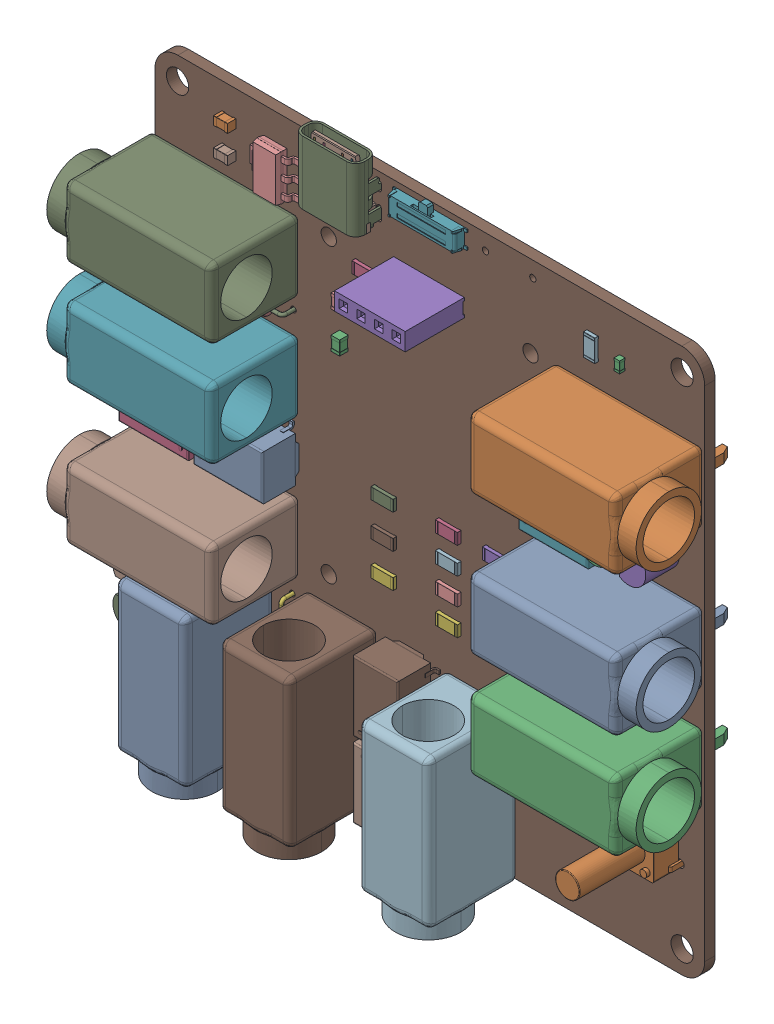
SolidWorks assembly PCB, configuration Default. Lengths in mm.
Overall size (84.69 83.26 18.9).
47 component instances, 13 part files, 0 mates.
Components (placement in the parent):
- Logic testing(2)-1: Logic testing(2) [Default] at origin size (84.69 83.26 18.9)
  - Relay_DPDT_Omron_G6K-2F-1: Relay_DPDT_Omron_G6K-2F [Default] at (-23.44 -1.875 1.595) x (0 1 0) z (0 0 1) size (7.8 10 5.58)
  - SW_PUSH_6mm_H13mm-1: SW_PUSH_6mm_H13mm [Default] at (36 -25.375 1.595) x (-1 0 0) z (0 0 1) size (7.17 6 16.5)
  - C_0603_1608Metric-1: C_0603_1608Metric [Default] at (27.75 32.875 1.595) x (0 1 0) z (0 0 1) size (1.6 0.8 0.8)
  - R_1206_3216Metric-1: R_1206_3216Metric [Default] at (-9 25.875 1.595) size (3.2 1.6 0.55)
  - PinSocket_1x04_P2.54mm_Vertical-1: PinSocket_1x04_P2.54mm_Vertical [Default] at (3.775 28.375 1.595) x (0 -1 0) z (0 0 1) size (2.54 10.16 11.6)
  - R_1206_3216Metric-2: R_1206_3216Metric [Default] at (9.75 -4.2083 1.595) size (3.2 1.6 0.55)
  - 4mm PCB Mount-1: 4mm PCB Mount [Default] at (-29.04 8.125 8.095) x (0 1 0) z (1 0 0) size (10.21 18.8 24)
  - 4mm PCB Mount-2: 4mm PCB Mount [Default] at (-29.04 -11.875 8.095) x (0 1 0) z (1 0 0) size (10.21 18.8 24)
  - 4mm PCB Mount-3: 4mm PCB Mount [Default] at (-29.04 23.125 8.095) x (0 1 0) z (1 0 0) size (10.21 18.8 24)
  - SOT-223-1: SOT-223 [Default] at (-22 32.375 1.595) x (-1 0 0) z (0 0 1) size (7 6.5 1.7)
  - R_1206_3216Metric-3: R_1206_3216Metric [Default] at (-6.25 -5.75 1.595) x (-1 0 0) z (0 0 1) size (3.2 1.6 0.55)
  - R_1206_3216Metric-4: R_1206_3216Metric [Default] at (23.5 32.875 1.595) x (0 1 0) z (0 0 1) size (3.2 1.6 0.55)
  - 4mm PCB Mount-4: 4mm PCB Mount [Default] at (29 3.375 8.095) x (0 -1 0) z (-1 0 0) size (10.21 18.8 24)
  - 4mm PCB Mount-5: 4mm PCB Mount [Default] at (29 23.375 8.095) x (0 -1 0) z (-1 0 0) size (10.21 18.8 24)
  - 4mm PCB Mount-6: 4mm PCB Mount [Default] at (29 -11.625 8.095) x (0 -1 0) z (-1 0 0) size (10.21 18.8 24)
  - R_1206_3216Metric-5: R_1206_3216Metric [Default] at (9.75 -8.0417 1.595) size (3.2 1.6 0.55)
  - TO-92_Inline-1: TO-92_Inline [Default] at (36 16.625 1.595) x (0 -1 0) z (0 0 1) size (4.83 3.75 9.8)
  - R_1206_3216Metric-6: R_1206_3216Metric [Default] at (3 -11.875 1.595) size (3.2 1.6 0.55)
  - SW_SP3T_PCM13-1: SW_SP3T_PCM13 [Default] at (0.25 36.745 1.595) x (-1 0 0) z (0 0 1) size (10.65 4.65 2)
  - TO-92_Inline-2: TO-92_Inline [Default] at (-37.02 -21.485 1.595) size (4.83 3.75 9.8)
  - USB_C_Receptacle_GCT_USB4085-1: USB_C_Receptacle_GCT_USB4085 [Default] at (-8.625 32.95 1.595) x (-1 0 0) z (0 0 1) size (8.94 9.17 5.56)
  - Relay_DPDT_Omron_G6K-2F-2: Relay_DPDT_Omron_G6K-2F [Default] at (23.25 13.375 1.595) x (0 1 0) z (0 0 1) size (7.8 10 5.58)
  - Relay_DPDT_Omron_G6K-2F-3: Relay_DPDT_Omron_G6K-2F [Default] at (-2.25 -33.275 1.595) size (7.8 10 5.58)
  - D_DO-35_SOD27_P7.62mm_Horizontal-1: D_DO-35_SOD27_P7.62mm_Horizontal [Default] at (-27.21 15.775 1.595) size (8.12 2.02 5.01)
  - Relay_DPDT_Omron_G6K-2F-4: Relay_DPDT_Omron_G6K-2F [Default] at (-2.25 -22.465 1.595) x (-1 0 0) z (0 0 1) size (7.8 10 5.58)
  - R_1206_3216Metric-7: R_1206_3216Metric [Default] at (3 -4.2083 1.595) x (-1 0 0) z (0 0 1) size (3.2 1.6 0.55)
  - D_DO-35_SOD27_P7.62mm_Horizontal-2: D_DO-35_SOD27_P7.62mm_Horizontal [Default] at (-19.75 -29.775 1.595) x (0 -1 0) z (0 0 1) size (8.12 2.02 5.01)
  - TO-92_Inline-3: TO-92_Inline [Default] at (31 16.645 1.595) x (0 -1 0) z (0 0 1) size (4.83 3.75 9.8)
  - Relay_DPDT_Omron_G6K-2F-5: Relay_DPDT_Omron_G6K-2F [Default] at (-34.19 -1.875 1.595) x (0 -1 0) z (0 0 1) size (7.8 10 5.58)
  - R_1206_3216Metric-8: R_1206_3216Metric [Default] at (9.75 -0.375 1.595) size (3.2 1.6 0.55)
  - R_1206_3216Metric-9: R_1206_3216Metric [Default] at (-6.25 -10.625 1.595) x (-1 0 0) z (0 0 1) size (3.2 1.6 0.55)
  - D_DO-35_SOD27_P7.62mm_Horizontal-3: D_DO-35_SOD27_P7.62mm_Horizontal [Default] at (-29.46 15.775 1.595) x (-1 0 0) z (0 0 1) size (8.12 2.02 5.01)
  - R_1206_3216Metric-10: R_1206_3216Metric [Default] at (-6.25 -0.875 1.595) x (-1 0 0) z (0 0 1) size (3.2 1.6 0.55)
  - R_1206_3216Metric-11: R_1206_3216Metric [Default] at (3 -8.0417 1.595) size (3.2 1.6 0.55)
  - 4mm PCB Mount-7: 4mm PCB Mount [Default] at (-12.25 -28.375 8.095) x (-1 0 0) z (0 1 0) size (10.21 18.8 24)
  - 4mm PCB Mount-8: 4mm PCB Mount [Default] at (7.75 -28.375 8.095) x (-1 0 0) z (0 1 0) size (10.21 18.8 24)
  - 4mm PCB Mount-9: 4mm PCB Mount [Default] at (-27.25 -28.375 8.095) x (-1 0 0) z (0 1 0) size (10.21 18.8 24)
  - C_0805_2012Metric-1: C_0805_2012Metric [Default] at (-28.75 34.875 1.595) x (-1 0 0) z (0 0 1) size (2 1.25 1.25)
  - C_0805_2012Metric-2: C_0805_2012Metric [Default] at (-12.25 15.625 1.595) x (0 1 0) z (0 0 1) size (2 1.25 1.25)
  - R_1206_3216Metric-12: R_1206_3216Metric [Default] at (3 -0.375 1.595) x (-1 0 0) z (0 0 1) size (3.2 1.6 0.55)
  - R_1206_3216Metric-13: R_1206_3216Metric [Default] at (9.75 -11.875 1.595) size (3.2 1.6 0.55)
  - D_DO-35_SOD27_P7.62mm_Horizontal-4: D_DO-35_SOD27_P7.62mm_Horizontal [Default] at (-19.75 -27.275 1.595) x (0 1 0) z (0 0 1) size (8.12 2.02 5.01)
  - C_0805_2012Metric-3: C_0805_2012Metric [Default] at (-28.75 30.875 1.595) x (-1 0 0) z (0 0 1) size (2 1.25 1.25)
  - TO-92_Inline-4: TO-92_Inline [Default] at (-34.48 -26.375 1.595) x (-1 0 0) z (0 0 1) size (4.83 3.75 9.8)
  - C_0805_2012Metric-4: C_0805_2012Metric [Default] at (-12.25 20.875 1.595) x (0 -1 0) z (0 0 1) size (2 1.25 1.25)
  - Logic testing_PCB-1: Logic testing_PCB [Default] at origin size (79 78.25 1.51)
